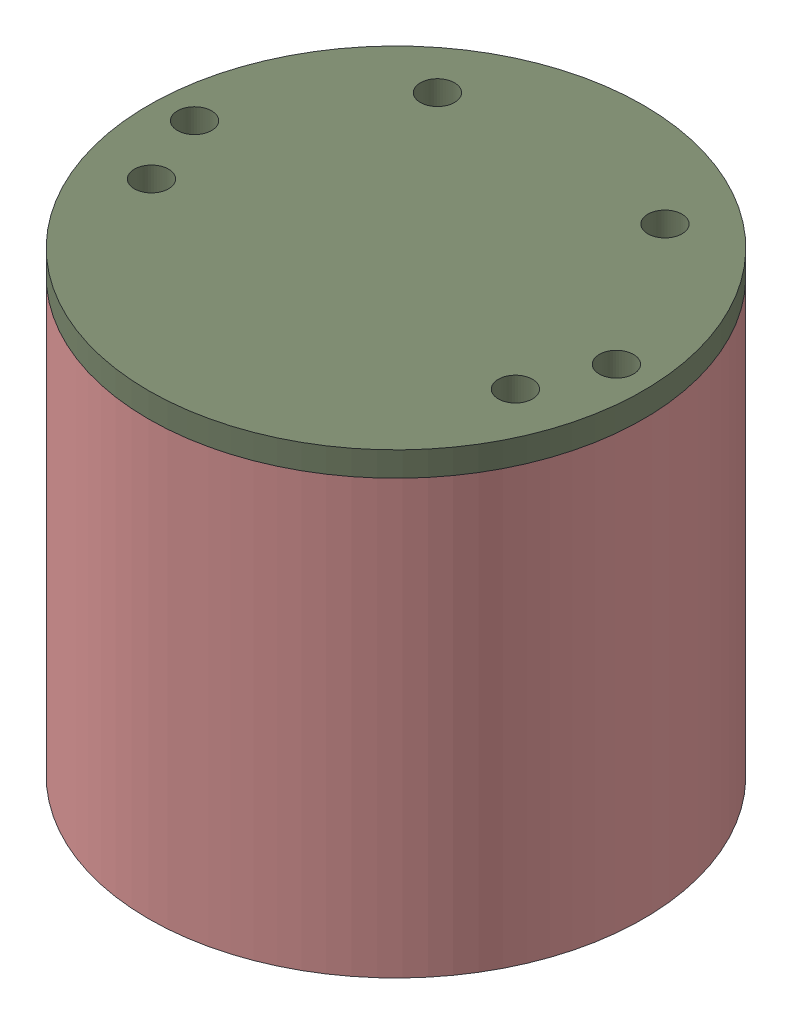
SolidWorks assembly battery_assembly, configuration Default. Lengths in mm.
Overall size (100.58 88 100.58).
11 component instances, 3 part files, 6 mates.
Components (placement in the parent):
- battery_pack-1: battery_pack [Default] at (30.2245 16.3919 39.6492) size (61.85 65 42.63)
  - 18650-9: 18650 [По умолчанию] x (0 1 0) z (0.875717 0 -0.482826) size (65 18.2 18.21)
  - 18650-10: 18650 [По умолчанию] at (-19.2128 0 0) x (0 1 0) z (0.168066 0 -0.985776) size (65 18.2 18.21)
  - 18650-11: 18650 [По умолчанию] at (-38.4256 0 0) x (0 1 0) z (-0.194298 0 0.980943) size (65 18.2 18.21)
  - 18650-12: 18650 [По умолчанию] at (-28.8192 0 -35.8516) x (0 1 0) z (-0.006073 0 0.999982) size (65 18.2 18.21) (hidden)
  - 18650-13: 18650 [По умолчанию] at (-38.4256 0 -19.2128) x (0 1 0) z (0.969487 0 -0.245141) size (65 18.2 18.21)
  - 18650-14: 18650 [По умолчанию] at (0 0 -19.2128) x (0 1 0) z (-0.065022 0 0.997884) size (65 18.2 18.21)
  - 18650-15: 18650 [По умолчанию] at (-19.2128 0 -19.2128) x (0 1 0) z (-0.082198 0 0.996616) size (65 18.2 18.21)
  - 18650-16: 18650 [По умолчанию] at (-9.6064 0 -35.8516) x (0 1 0) z (-0.088185 0 0.996104) size (65 18.2 18.21) (hidden)
- cover-1: cover [Default] at (11.0117 84.1319 30.0428) size (100.58 5 100.58) (hidden)
- holder-1: holder [Default] at (11.0117 -3.8681 30.0428) size (100.58 88 100.58)
Mates (geometry in assembly coordinates):
- Concentric1: concentric aligned: cylinder of cover-1 through (48.0122 89.1319 42.7614) axis (0 -1 0) radius 3.475; cylinder of holder-1 through (48.0122 84.1319 42.7614) axis (0 -1 0) radius 3.475
- Coincident2: coincident anti-aligned: plane of cover-1 through (11.0117 84.1319 30.0428) normal (0 -1 0); plane of holder-1 through (11.0117 84.1319 30.0428) normal (0 1 0)
- Parallel1: parallel anti-aligned: plane of battery_pack-1/18650-15 through (11.0117 16.3919 20.4364) normal (0 -1 0); plane of holder-1 through (11.0117 16.0919 30.0428) normal (0 1 0)
- Concentric3: concentric aligned: circle of battery_pack-1; circle of holder-1
- Parallel2: parallel anti-aligned: line of battery_pack-1 through (-8.2011 16.3919 39.6492) axis (0 0 -1); line of holder-1 through (-19.3994 84.1319 9.6428) axis (0 0 1)
- Coincident3: coincident anti-aligned: plane of battery_pack-1/18650-11 through (-2.3155 16.0919 40.815) normal (0 -1 0); plane of holder-1 through (11.0117 16.0919 30.0428) normal (0 1 0)
